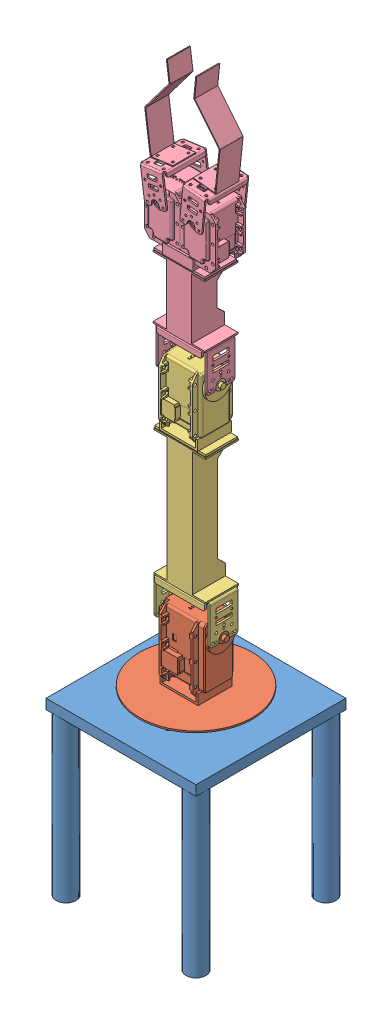
SolidWorks assembly CrawlerValidation, configuration Default. Lengths in mm.
Overall size (293.17 732.07 258.28).
4 component instances, 4 part files, 6 mates.
Components (placement in the parent):
- Base-1: Base [Default] at (7.5511 -195.7673 -43.0356) size (150 180.4 150)
- Link1-3: Link1 [Default] at (-102.4906 38.442 208.8341) x (0.001255 0 -0.999999) z (0.999999 0 0.001255) size (113 71.98 113)
- Link2-1: Link2 [Default] at (-102.4028 43.1485 138.8802) x (0.000956 0.648278 -0.761403) z (0.999999 0 0.001255) size (172.38 195.85 56)
- Link3NEW2-1: Link3NEW2 [Default] at (134.4881 439.7799 -183.0875) x (0.790051 -0.57228 -0.219805) z (-0.61304 -0.736835 -0.285055) size (193.44 120.16 228.69)
Mates (geometry in assembly coordinates):
- Coincident1: coincident anti-aligned: plane of Link1-3 through (1.9302 79.1695 180.4) normal (0 -1 0); plane of Base-1 through (4.7132 79.1695 177.617) normal (0 1 0)
- Concentric2: concentric aligned: circle of Link1-3; circle of Base-1
- Concentric3: concentric aligned: cylinder of Link1-3 through (29.7482 135.8295 180.4169) axis (-0.999999 0 -0.001255) radius 5; cylinder of Link2-1 through (29.9482 135.8295 180.4172) axis (-0.999999 0 -0.001255) radius 5
- Coincident2: coincident anti-aligned: plane of Link1-3 through (27.966 149.9975 166.2467) normal (0.999999 0 0.001255); plane of Link2-1 through (27.9307 132.8295 194.4146) normal (-0.999999 0 -0.001255)
- Concentric5: concentric aligned: cylinder of Link2-1 through (26.9158 353.4895 180.7134) axis (-0.999999 0 -0.001255) radius 5; cylinder of Link3NEW2-1 through (27.1158 353.4895 180.7136) axis (-0.999999 0 -0.001255) radius 5
- Coincident5: coincident anti-aligned: plane of Link2-1 through (25.1336 367.6575 166.5431) normal (0.999999 0 0.001255); plane of Link3NEW2-1 through (25.0983 350.4895 194.7111) normal (-0.999999 0 -0.001255)
